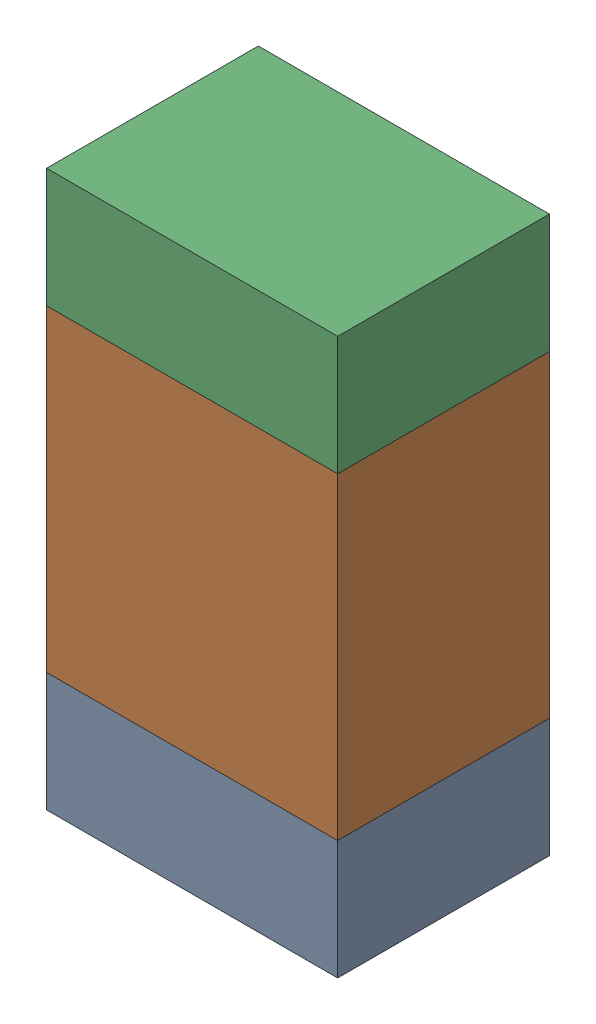
SolidWorks assembly R603_3PCB, configuration Default. Lengths in mm.
Overall size (0.55 1.05 0.4).
6 component instances, 2 part files, 0 mates.
Components (placement in the parent):
- 846483288-1: 846483288 [Default] at (104.8001 94.3376 -2.0638) size (0.55 0.22 0.4)
  - Extruded_12-1: Extruded_12 [Default] at origin size (0.55 0.22 0.4)
- 846483424-1: 846483424 [Default] at (104.8001 94.7501 -2.0638) size (0.55 0.6 0.4)
  - Extruded_13-1: Extruded_13 [Default] at origin size (0.55 0.6 0.4)
- 846483288-2: 846483288 [Default] at (104.8001 95.1626 -2.0638) size (0.55 0.22 0.4)
  - Extruded_12-1: Extruded_12 [Default] at origin size (0.55 0.22 0.4)
